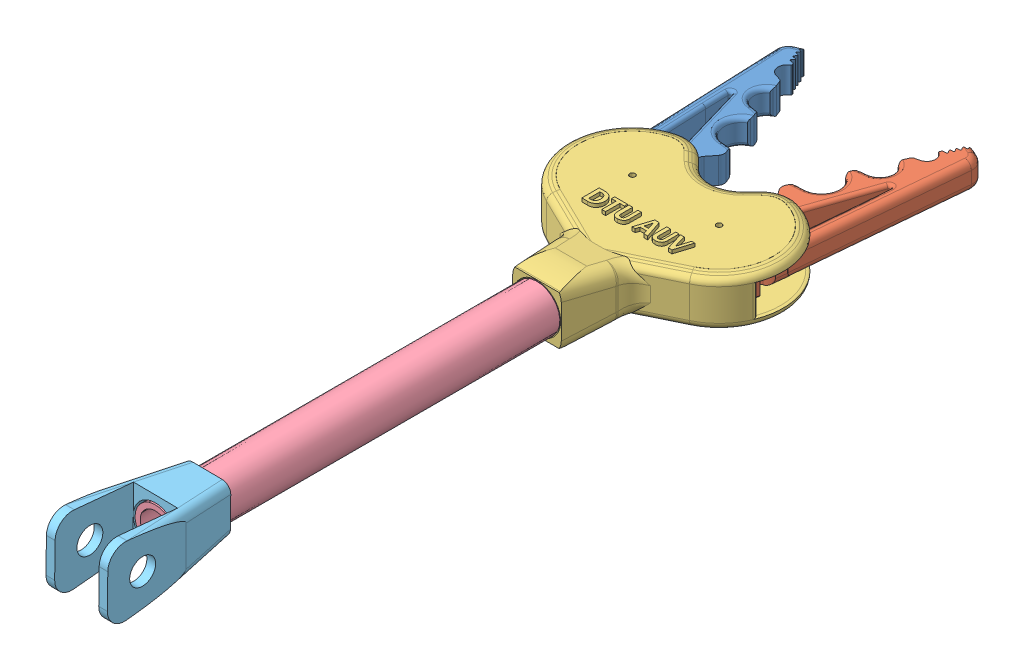
SolidWorks assembly Gripper_assembly_v1, configuration Default. Lengths in mm.
Overall size (194.29 43.55 467.12).
5 component instances, 5 part files, 11 mates.
Components (placement in the parent):
- Left_part-1: Left_part [Default] at (88.6394 -109.3077 66.6462) x (0.930793 0 -0.365547) z (0.365547 0 0.930793) size (56 15.47 148)
- Right_part-1: Right_part [Default] at (208.8655 -109.3077 23.1253) x (0.911753 0 0.410738) z (-0.410738 0 0.911753) size (55 15.88 147.5)
- Gripv2-2: Gripv2 [Default] at (204.2515 -47.2807 210.5291) x (-1 0 0) z (0 0 1) size (124 31.83 116.32)
- PVC_arm-1: PVC_arm [Default] at (197.9825 -38.5307 526.869) x (-0.196013 -0.980601 0) z (0.980601 -0.196013 0) size (26.4 250 26.4)
- servo_mount'-1: servo_mount' [Default] at (197.9714 -39.5307 534.369) x (-0.999938 0.011121 0) z (0 0 -1) size (35.4 43.16 75.19)
Mates (geometry in assembly coordinates):
- Coincident1: coincident aligned: plane of Left_part-1 through (172.9825 -31.0307 226.869) normal (0 1 0); plane of Right_part-1 through (222.9825 -31.0307 226.869) normal (0 1 0)
- GearMate6: gear = 19.2 : 19.2 mm: cylinder of Left_part-1 through (205.4407 -18.876 254.93) axis (0 1 0) radius 9.6; cylinder of Right_part-1 through (213.6639 -18.876 235.7901) axis (0 1 0) radius 9.6
- Coincident7: coincident anti-aligned: plane of Left_part-1; plane of Right_part-1
- Concentric12: concentric anti-aligned: circle of Right_part-1; circle of Gripv2-2
- Concentric13: concentric anti-aligned: circle of Left_part-1; circle of Gripv2-2
- Parallel5: parallel anti-aligned: plane of Gripv2-2 through (172.9825 -52.2807 226.869) normal (0 -1 0)
- Distance5: distance = 1.25 mm anti-aligned: plane of Gripv2-2 through (172.9825 -47.2807 226.869) normal (0 1 0); plane of Right_part-1 through (222.9825 -46.0307 226.869) normal (0 -1 0)
- Coincident28: coincident anti-aligned: plane of Gripv2-2 through (187.2825 -47.1752 306.869) normal (0 0 1); plane of PVC_arm-1 through (197.9825 -38.5307 306.869) normal (0 0 -1)
- Concentric15: concentric anti-aligned: circle of Gripv2-2; circle of PVC_arm-1
- Concentric16: concentric aligned: cylinder of PVC_arm-1 through (197.9825 -38.5307 496.869) axis (0 0 -1) radius 13.2; circle of servo_mount'-1
- Coincident29: coincident anti-aligned: plane of PVC_arm-1 through (197.9825 -38.5307 496.869) normal (0 0 1); plane of servo_mount'-1 through (180.4359 -24.6347 496.869) normal (0 0 -1)
